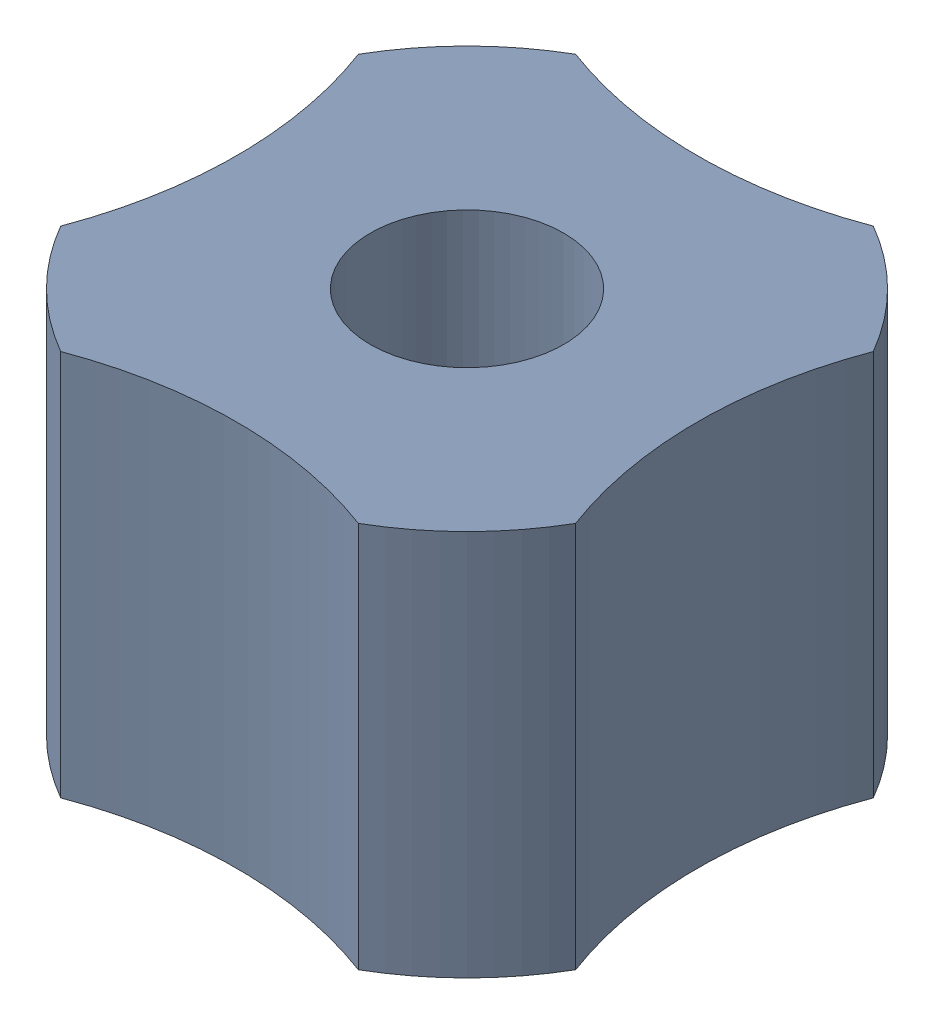
SolidWorks assembly MFG CW Spring Adj Knob Asmbly, configuration Default. Lengths in mm.
Overall size (17.32 13 17.32).
2 component instances, 2 part files, 0 mates.
Components (placement in the parent):
- MFG CW Spring Adj Knob-1: MFG CW Spring Adj Knob [Default] at origin size (17.32 13 17.32)
- M6 x 1 Hex Nut-1: M6 x 1 Hex Nut [Default] at (0 31.5 0) x (1 0 0) z (0 1 0) size (10 11.55 5)
